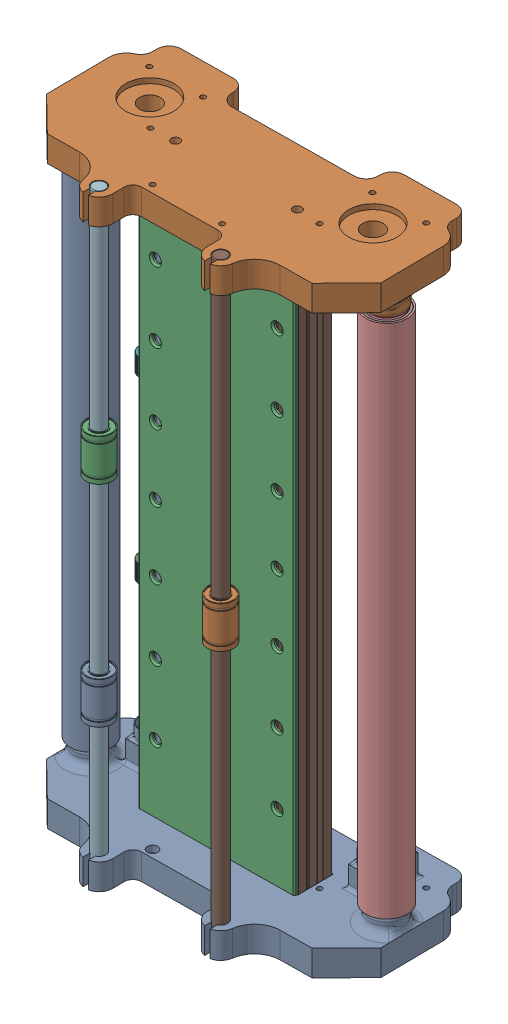
SolidWorks assembly Artisan_V1.0, configuration Défaut. Lengths in mm.
Overall size (193.99 350 103.37).
26 component instances, 10 part files, 50 mates.
Components (placement in the parent):
- Tube_Alu_24Di_22De_300mm_V1.0-1: Tube_Alu_24Di_22De_300mm_V1.0 [Défaut] at (8.8286 48.7862 122.2557) x (1 0 0) z (0 -1 0) size (24 24 300)
- Ball_Bearing_608ZZ_V1.0-1: Ball_Bearing_608ZZ_V1.0 [Défaut] at (8.8286 45.2862 122.2557) x (1 0 0) z (0 1 0) size (22 22 7)
- Ball_Bearing_608ZZ_V1.0-2: Ball_Bearing_608ZZ_V1.0 [Défaut] at (8.8286 -247.7138 122.2557) x (1 0 0) z (0 -1 0) size (22 22 7)
- Ball_Bearing_608ZZ_V1.0-3: Ball_Bearing_608ZZ_V1.0 [Défaut] at (178.818 -247.7138 120.3582) x (1 0 0) z (0 -1 0) size (22 22 7)
- Ball_Bearing_608ZZ_V1.0-4: Ball_Bearing_608ZZ_V1.0 [Défaut] at (178.818 45.2862 120.3582) x (1 0 0) z (0 1 0) size (22 22 7)
- Tube_Alu_24Di_22De_300mm_V1.0-2: Tube_Alu_24Di_22De_300mm_V1.0 [Défaut] at (178.818 48.7862 120.3582) x (1 0 0) z (0 -1 0) size (24 24 300)
- Profil_Alu_2020_VSLOT-400mm_V1.0-1: Profil_Alu_2020_VSLOT-400mm_V1.0 [Défaut] at (118.3083 68.8862 122.0467) x (0.999938 0 -0.011162) z (0 -1 0) size (20 20 340.04)
- Profil_Alu_2020_VSLOT-400mm_V1.0-2: Profil_Alu_2020_VSLOT-400mm_V1.0 [Défaut] at (48.2126 68.8862 122.8291) x (0.999938 0 -0.011162) z (0 -1 0) size (20 20 340.04)
- Printed_Right_Body_V1.0-2: Printed_Right_Body_V1.0 [Défaut] at (93.8386 -276.1138 122.6746) x (0.999938 0 -0.011162) z (0 1 0) size (192.3 101.23 35)
- Printed_Right_Body_V1.0-3: Printed_Right_Body_V1.0 [Défaut] at (93.8386 73.6862 122.6746) x (-0.999938 0 0.011162) z (0 -1 0) size (192.3 101.23 35)
- Alu_plaque_320_90_2mm_V1.0-1: Alu_plaque_320_90_2mm_V1.0 [Défaut] at (93.9996 -101.1138 132.6235) x (0.999938 0 -0.011162) z (0.011162 0 0.999938) size (90 320 2)
- Kysan 1124090-3: Kysan 1124090 [Default] at (29.5302 -284.1138 108.7593) x (-0.999938 0 0.011162) z (0 1 0) (suppressed, hidden)
- Tube_Alu_8Di_7De_300mm_V1.0-3: Tube_Alu_8Di_7De_300mm_V1.0 [Défaut] at (29.5302 61.8862 108.7593) x (1 0 0) z (0 -1 0) size (8 8 335)
- Tube_Alu_8Di_7De_300mm_V1.0-4: Tube_Alu_8Di_7De_300mm_V1.0 [Défaut] at (29.3951 70.5249 96.6601) x (1 0 0) z (0 -1 0) size (8 8 335)
- Kysan 1124090-4: Kysan 1124090 [Default] at (157.8204 -284.1138 107.3273) x (-0.999938 0 0.011162) z (0 1 0) (suppressed, hidden)
- Tube_Alu_8Di_7De_300mm_V1.0-5: Tube_Alu_8Di_7De_300mm_V1.0 [Défaut] at (157.8204 61.8862 107.3273) x (1 0 0) z (0 -1 0) size (8 8 335)
- Gear_Wheel_V1.0-1: Gear_Wheel_V1.0 [Défaut] at (29.5302 -54.2883 108.7593) x (1 0 0) z (0 -1 0) size (12.2 12.19 10)
- Gear_Wheel_V1.0-2: Gear_Wheel_V1.0 [Défaut] at (29.3951 -54.2883 96.6601) x (1 0 0) z (0 -1 0) size (12.2 12.19 10)
- Gear_Wheel_V1.0-3: Gear_Wheel_V1.0 [Défaut] at (29.5302 -158.3532 108.7593) x (1 0 0) z (0 -1 0) size (12.2 12.19 10)
- Gear_Wheel_V1.0-4: Gear_Wheel_V1.0 [Défaut] at (29.3951 -159.9808 96.6601) x (1 0 0) z (0 -1 0) size (12.2 12.19 10)
- Kysan 1124090-5: Kysan 1124090 [Default] at (93.0376 -302.9495 141.2395) x (-0.999938 0 0.011162) z (0.011162 0 0.999938) (suppressed, hidden)
- Road_D8x350mm_V1.0-1: Road_D8x350mm_V1.0 [Défaut] at (129.3395 73.6862 167.3542) x (1 0 0) z (0 -1 0) size (8 8 350)
- Road_D8x350mm_V1.0-2: Road_D8x350mm_V1.0 [Défaut] at (59.3436 73.6862 168.1157) x (1 0 0) z (0 -1 0) size (8 8 350)
- Lineare_Bearing_Lm8uu_V1.0-1: Lineare_Bearing_Lm8uu_V1.0 [Default] at (59.3436 -181.6143 168.1157) x (1 0 0) z (0 -1 0) size (15 15 24)
- Lineare_Bearing_Lm8uu_V1.0-2: Lineare_Bearing_Lm8uu_V1.0 [Default] at (129.3395 -108.8531 167.3542) x (1 0 0) z (0 -1 0) size (15 15 24)
- Lineare_Bearing_Lm8uu_V1.0-3: Lineare_Bearing_Lm8uu_V1.0 [Default] at (59.3436 -59.3122 168.1157) x (1 0 0) z (0 -1 0) size (15 15 24)
Mates (geometry in assembly coordinates):
- Coaxiale2: concentric aligned: cylinder of Tube_aluminium_24_22_300mm-1 through (8.8286 -251.2138 122.2557) axis (0 1 0) radius 11; cylinder of Ball_Bearing_608ZZ-1 through (8.8286 280.3365 122.2557) axis (0 1 0) radius 11
- Coïncidente2: coincident aligned: plane of Tube_aluminium_24_22_300mm-1 through (8.8286 48.7862 122.2557) normal (0 1 0); plane of Ball_Bearing_608ZZ-1 through (8.8286 48.7862 122.2557) normal (0 1 0)
- Coaxiale3: concentric anti-aligned: cylinder of Tube_aluminium_24_22_300mm-1 through (8.8286 -251.2138 122.2557) axis (0 1 0) radius 11; cylinder of Ball_Bearing_608ZZ-2 through (8.8286 -482.7641 122.2557) axis (0 -1 0) radius 11
- Coïncidente3: coincident aligned: plane of Tube_aluminium_24_22_300mm-1 through (8.8286 -251.2138 122.2557) normal (0 -1 0); plane of Ball_Bearing_608ZZ-2 through (8.8286 -251.2138 122.2557) normal (0 -1 0)
- Coïncidente4: coincident aligned: plane of Ball_Bearing_608ZZ-3 through (178.818 -251.2138 120.3582) normal (0 -1 0); plane of Tube_aluminium_24_22_300mm-2 through (178.818 -251.2138 120.3582) normal (0 -1 0)
- Coïncidente5: coincident aligned: plane of Ball_Bearing_608ZZ-4 through (178.818 48.7862 120.3582) normal (0 1 0); plane of Tube_aluminium_24_22_300mm-2 through (178.818 48.7862 120.3582) normal (0 1 0)
- Coaxiale4: concentric anti-aligned: cylinder of Ball_Bearing_608ZZ-3 through (178.818 -482.7641 120.3582) axis (0 -1 0) radius 11; cylinder of Tube_aluminium_24_22_300mm-2 through (178.818 -251.2138 120.3582) axis (0 1 0) radius 11
- Coaxiale5: concentric aligned: cylinder of Ball_Bearing_608ZZ-4 through (178.818 280.3365 120.3582) axis (0 1 0) radius 11; cylinder of Tube_aluminium_24_22_300mm-2 through (178.818 -251.2138 120.3582) axis (0 1 0) radius 11
- Coïncidente9: coincident aligned: plane of Profil├®_aluminium_2020_VSLOT-40cm-1 through (137.1496 -271.1138 118.941) normal (0 -1 0); plane of Profil├®_aluminium_2020_VSLOT-40cm-2 through (67.054 -271.1138 119.7234) normal (0 -1 0)
- Coïncidente10: coincident aligned: plane of Profil├®_aluminium_2020_VSLOT-40cm-1 through (124.1149 -271.1138 132.2873) normal (0.011162 0 0.999938); plane of Profil├®_aluminium_2020_VSLOT-40cm-2 through (68.6012 -271.1138 132.907) normal (0.011162 0 0.999938)
- Coïncidente11: coincident anti-aligned: plane of Profil├®_aluminium_2020_VSLOT-40cm-2 through (67.054 -271.1138 119.7234) normal (0 -1 0); plane of corps_droite-2 through (93.8386 -271.1138 122.6746) normal (0 1 0)
- Coïncidente12: coincident anti-aligned: plane of Profil├®_aluminium_2020_VSLOT-40cm-2 through (48.9792 -271.1138 113.1247) normal (-0.011162 0 -0.999938); plane of corps_droite-2 through (68.778 -261.1138 112.9037) normal (0.011162 0 0.999938)
- Coïncidente13: coincident anti-aligned: plane of Profil├®_aluminium_2020_VSLOT-40cm-2 through (48.8991 -271.1138 132.8269) normal (-0.999938 0 0.011162); plane of corps_droite-2 through (48.6792 -261.1138 113.1281) normal (0.999938 0 -0.011162)
- Coïncidente14: coincident anti-aligned: plane of Profil├®_aluminium_2020_VSLOT-40cm-1 through (138.777 -271.1138 112.4224) normal (0.999938 0 -0.011162); plane of corps_droite-2 through (138.7736 -261.1138 112.1224) normal (-0.999938 0 0.011162)
- Coaxiale6: concentric aligned: cylinder of Ball_Bearing_608ZZ-3 through (178.818 -482.7641 120.3582) axis (0 -1 0) radius 4; cylinder of corps_droite-2 through (178.818 -241.1138 120.3582) axis (0 -1 0) radius 4
- Coïncidente15: coincident anti-aligned: plane of Ball_Bearing_608ZZ-3 through (178.818 -251.1138 126.3082) normal (0 -1 0); plane of corps_droite-2 through (178.818 -251.1138 120.3582) normal (0 1 0)
- Coaxiale7: concentric aligned: cylinder of Ball_Bearing_608ZZ-2 through (8.8286 -482.7641 122.2557) axis (0 -1 0) radius 4; cylinder of corps_droite-2 through (8.8286 -241.1138 122.2557) axis (0 -1 0) radius 4
- Coïncidente16: coincident anti-aligned: plane of Ball_Bearing_608ZZ-2 through (8.8286 -251.1138 128.2057) normal (0 -1 0); plane of corps_droite-2 through (8.8286 -251.1138 122.2557) normal (0 1 0)
- Coaxiale10: concentric aligned: cylinder of Ball_Bearing_608ZZ-4 through (178.818 280.3365 120.3582) axis (0 1 0) radius 4; cylinder of corps_droite-3 through (178.818 38.6862 120.3582) axis (0 1 0) radius 4
- Coaxiale11: concentric aligned: cylinder of Ball_Bearing_608ZZ-1 through (8.8286 280.3365 122.2557) axis (0 1 0) radius 4; cylinder of corps_droite-3 through (8.8286 38.6862 122.2557) axis (0 1 0) radius 4
- Coïncidente17: coincident anti-aligned: plane of Ball_Bearing_608ZZ-1 through (8.8286 48.6862 116.3057) normal (0 1 0); plane of corps_droite-3 through (8.8286 48.6862 122.2557) normal (0 -1 0)
- Coïncidente18: coincident aligned: plane of Profil├®_aluminium_2020_VSLOT-40cm-1 through (138.9397 -271.1138 127.0044) normal (0.999938 0 -0.011162); plane of plaque-1 through (139.0192 58.8862 134.1211) normal (0.999938 0 -0.011162)
- Coïncidente19: coincident anti-aligned: plane of corps_droite-2 through (93.8386 -261.1138 122.6746) normal (0 1 0); plane of plaque-1 through (139.0192 -261.1138 134.1211) normal (0 -1 0)
- Coïncidente20: coincident anti-aligned: plane of Profil├®_aluminium_2020_VSLOT-40cm-2 through (54.0193 -271.1138 133.0697) normal (0.011162 0 0.999938); plane of plaque-1 through (93.9996 -101.1138 132.6235) normal (-0.011162 0 -0.999938)
- Coaxiale15: concentric anti-aligned: circle of corps_droite-2; circle of Kysan 1124090-3
- Coaxiale19: concentric anti-aligned: circle of corps_droite-2; circle of Kysan 1124090-3
- Coaxiale20: concentric aligned: cylinder of corps_droite-2 through (29.3951 -271.2138 96.6601) axis (0 1 0) radius 6; cylinder of Tube_aluminium_8_7_300mm-4 through (29.3951 -264.4751 96.6601) axis (0 1 0) radius 4
- Coaxiale21: concentric anti-aligned: circle of corps_droite-2; circle of Kysan 1124090-4
- Coïncidente39: coincident aligned: cylinder of corps_droite-2 through (173.1464 -561.1138 91.6553) axis (0 1 0) radius 1.5; circle of Kysan 1124090-4
- Coïncidente40: coincident aligned: plane of Kysan 1124090-3 through (29.5302 -276.1138 108.7593) normal (0 1 0); plane of Kysan 1124090-4 through (157.8204 -276.1138 107.3273) normal (0 1 0)
- Coaxiale22: concentric aligned: cylinder of Kysan 1124090-4 through (157.8204 -252.1138 107.3273) axis (0 1 0) radius 2.5; cylinder of Tube_aluminium_8_7_300mm-5 through (157.8204 -273.1138 107.3273) axis (0 1 0) radius 3.5
- Coaxiale23: concentric aligned: cylinder of Kysan 1124090-3 through (29.5302 -252.1138 108.7593) axis (0 1 0) radius 2.5; cylinder of Tube_aluminium_8_7_300mm-3 through (29.5302 -273.1138 108.7593) axis (0 1 0) radius 3.5
- Coïncidente41: coincident anti-aligned: plane of Kysan 1124090-3 through (29.5302 -273.1138 108.7593) normal (0 1 0); plane of Tube_aluminium_8_7_300mm-3 through (29.5302 -273.1138 108.7593) normal (0 -1 0)
- Coïncidente42: coincident anti-aligned: plane of Kysan 1124090-4 through (157.8204 -273.1138 107.3273) normal (0 1 0); plane of Tube_aluminium_8_7_300mm-5 through (157.8204 -273.1138 107.3273) normal (0 -1 0)
- Coaxiale24: concentric aligned: cylinder of Tube_aluminium_8_7_300mm-3 through (29.5302 -273.1138 108.7593) axis (0 1 0) radius 4; cylinder of roue d'engrenage-1 through (29.5302 -64.2883 108.7593) axis (0 1 0) radius 4
- Coaxiale25: concentric aligned: cylinder of Tube_aluminium_8_7_300mm-4 through (29.3951 -264.4751 96.6601) axis (0 1 0) radius 4; cylinder of roue d'engrenage-2 through (29.3951 -64.2883 96.6601) axis (0 1 0) radius 4
- Coïncidente43: coincident aligned: plane of roue d'engrenage-1 through (29.5302 -64.2883 108.7593) normal (0 -1 0); plane of roue d'engrenage-2 through (29.3951 -64.2883 96.6601) normal (0 -1 0)
- Parallèle1: parallel anti-aligned: plane of corps_droite-2 through (93.8386 -276.1138 122.6746) normal (0 -1 0); plane of Kysan 1124090-5 through (79.2036 -281.9495 111.392) normal (0 1 0)
- Coaxiale26: concentric anti-aligned: cylinder of corps_droite-3 through (129.3395 98.8614 167.3542) axis (0 -1 0) radius 3.9819; cylinder of Road_D8x350mm-1 through (129.3395 -276.3138 167.3542) axis (0 1 0) radius 4
- Coïncidente44: coincident aligned: plane of corps_droite-3 through (93.8386 73.6862 122.6746) normal (0 1 0); plane of Road_D8x350mm-1 through (129.3395 73.6862 167.3542) normal (0 1 0)
- Coaxiale27: concentric anti-aligned: cylinder of corps_droite-3 through (59.3436 98.8614 168.1157) axis (0 -1 0) radius 4; cylinder of Road_D8x350mm-2 through (59.3436 -276.3138 168.1157) axis (0 1 0) radius 4
- Coïncidente45: coincident aligned: plane of corps_droite-3 through (93.8386 73.6862 122.6746) normal (0 1 0); plane of Road_D8x350mm-2 through (59.3436 73.6862 168.1157) normal (0 1 0)
- Coaxiale28: concentric aligned: cylinder of Tube_aluminium_8_7_300mm-3 through (29.5302 -273.1138 108.7593) axis (0 1 0) radius 4; cylinder of roue d'engrenage-3 through (29.5302 -168.3532 108.7593) axis (0 1 0) radius 4
- Coaxiale29: concentric aligned: cylinder of Tube_aluminium_8_7_300mm-4 through (29.3951 -264.4751 96.6601) axis (0 1 0) radius 4; cylinder of roue d'engrenage-4 through (29.3951 -169.9808 96.6601) axis (0 1 0) radius 4
- Coaxiale30: concentric aligned: cylinder of Road_D8x350mm-2 through (59.3436 -276.3138 168.1157) axis (0 1 0) radius 4; cylinder of lm8uu-1 through (59.3436 -193.6143 168.1157) axis (0 1 0) radius 4
- Coaxiale31: concentric aligned: cylinder of Road_D8x350mm-1 through (129.3395 -276.3138 167.3542) axis (0 1 0) radius 4; cylinder of lm8uu-2 through (129.3395 -120.8531 167.3542) axis (0 1 0) radius 4
- Coaxiale32: concentric aligned: cylinder of Road_D8x350mm-2 through (59.3436 -276.3138 168.1157) axis (0 1 0) radius 4; cylinder of lm8uu-3 through (59.3436 -71.3122 168.1157) axis (0 1 0) radius 4
- Verrouiller1: lock: unknown of Profil├®_aluminium_2020_VSLOT-40cm-2; unknown of corps_droite-3
- Coïncidente47: coincident anti-aligned: plane of corps_droite-2 through (93.8386 -276.1138 122.6746) normal (0 -1 0); plane of Kysan 1124090-3 through (29.5302 -276.1138 108.7593) normal (0 1 0)
- Parallèle2: parallel aligned: plane of corps_droite-2 through (-1.9321 -271.1138 157.1135) normal (0.011162 0 0.999938); plane of Kysan 1124090-5 through (93.1269 -302.9495 149.239) normal (0.011162 0 0.999938)
